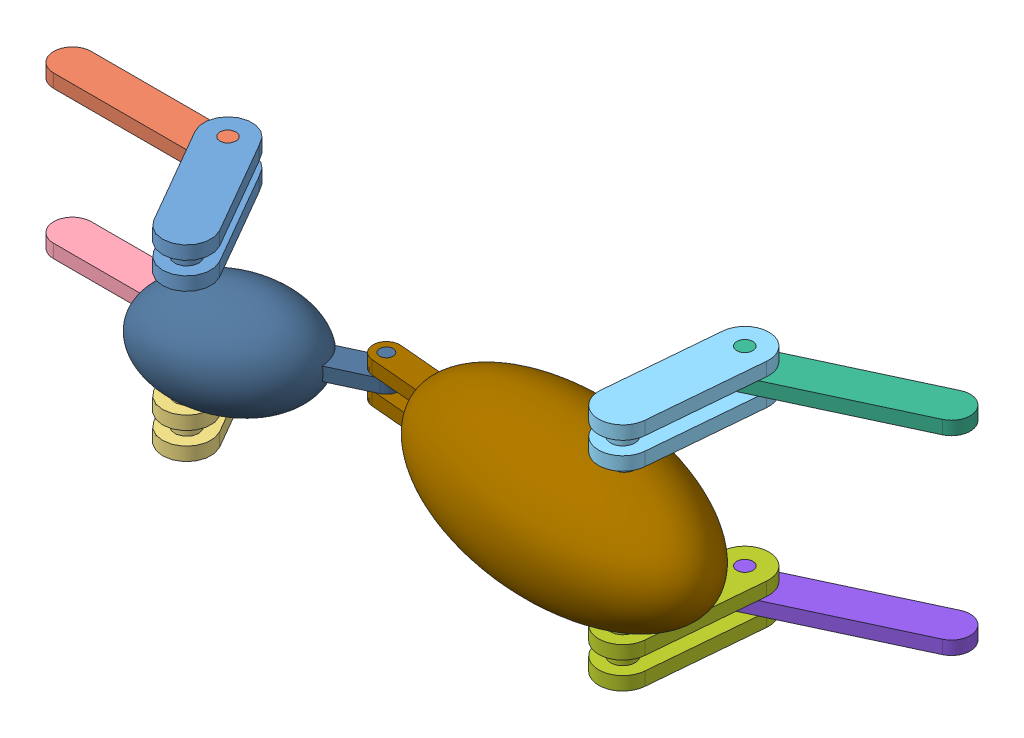
SolidWorks assembly cheetah_assy, configuration По умолчанию. Lengths in mm.
Overall size (1483.26 430 531.22).
10 component instances, 10 part files, 8 mates.
Components (placement in the parent):
- bl_hip-1: bl_hip [По умолчанию] at origin size (195 125 271.87)
- bl_knee-1: bl_knee [По умолчанию] at (-5 0 -8.6603) size (360 75 70)
- br_hip-1: br_hip [По умолчанию] x (1 0 0) z (0 0 -1) size (195 125 271.87)
- br_knee-1: br_knee [По умолчанию] at (-5 -275 -223.4618) size (360 75 70)
- fl_hip-1: fl_hip [По умолчанию] at origin size (108.3 165 299.2)
- fl_knee-1: fl_knee [По умолчанию] at origin size (332.83 75 192.56)
- fr_hip-1: fr_hip [По умолчанию] x (1 0 0) z (0 0 -1) size (108.3 165 299.2)
- fr_knee-1: fr_knee [По умолчанию] x (1 0 0) z (0 0 -1) size (332.83 75 192.56)
- spine_a-1: spine_a [По умолчанию] at origin size (682.56 280 299.88)
- spine_b-1: spine_b [По умолчанию] at origin size (372.87 195 256.91)
Mates (geometry in assembly coordinates):
- Concentric8: concentric aligned: cylinder of fl_hip-1 through (425.4869 190 -219.556) axis (0 1 0) radius 45; cylinder of fl_knee-1 through (425.4869 140 -219.556) axis (0 1 0) radius 15
- Coincident9: coincident aligned: plane of fl_hip-1 through (416.3356 140 -114.9556) normal (0 -1 0); plane of fl_knee-1 through (425.4869 140 -219.556) normal (0 -1 0)
- Parallel1: parallel aligned: plane of bl_knee-1 through (-554.9441 125 -81.061) normal (0 0 1)
- Concentric10: concentric aligned: cylinder of br_knee-1 through (-434.9441 -175 -116.061) axis (0 -1 0) radius 15; cylinder of br_hip-1 through (-434.9441 -50 -116.061) axis (0 -1 0) radius 15
- Coincident12: coincident aligned: plane of bl_knee-1 through (-554.9441 125 -81.061) normal (0 0 1); plane of br_knee-1 through (-434.9441 -150 -81.061) normal (0 0 1)
- Coincident13: coincident aligned: plane of br_hip-1 through (-379.9441 -175 -20.7982) normal (0 -1 0); plane of br_knee-1 through (-434.9441 -175 -116.061) normal (0 -1 0)
- Concentric11: concentric anti-aligned: cylinder of bl_knee-1 through (-434.9441 100 -116.061) axis (0 1 0) radius 15; cylinder of bl_hip-1 through (-434.9441 175 -116.061) axis (0 -1 0) radius 15
- Coincident14: coincident aligned: plane of bl_hip-1 through (-379.9441 100 -20.7982) normal (0 -1 0); plane of bl_knee-1 through (-434.9441 100 -116.061) normal (0 -1 0)
